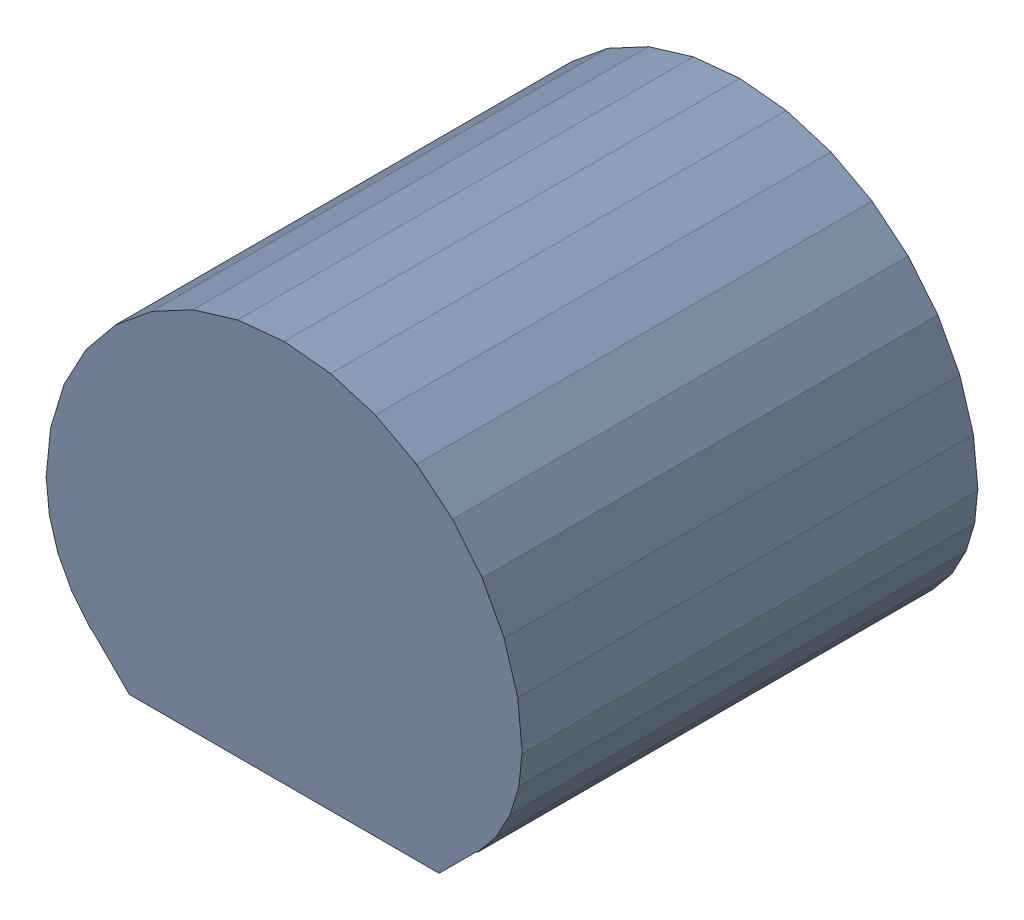
SolidWorks assembly User Library-TO-92_Str_BODY, configuration Default. Lengths in mm.
Overall size (5.23 4.2 5).
3 component instances, 1 part files, 0 mates.
Components (placement in the parent):
- User Library-TO-92_Str_Open_CASCADE_STEP_translator_6.2_1.1-1: User Library-TO-92_Str_Open_CASCADE_STEP_translator_6.2_1.1 [Default] at origin size (5.23 4.2 5)
  - User Library-TO-92_Str_547225856-1: User Library-TO-92_Str_547225856 [Default] at (0 0.5113 5) size (5.23 4.2 5)
    - User Library-TO-92_Str_Extruded-1: User Library-TO-92_Str_Extruded [Default] at origin size (5.23 4.2 5)
